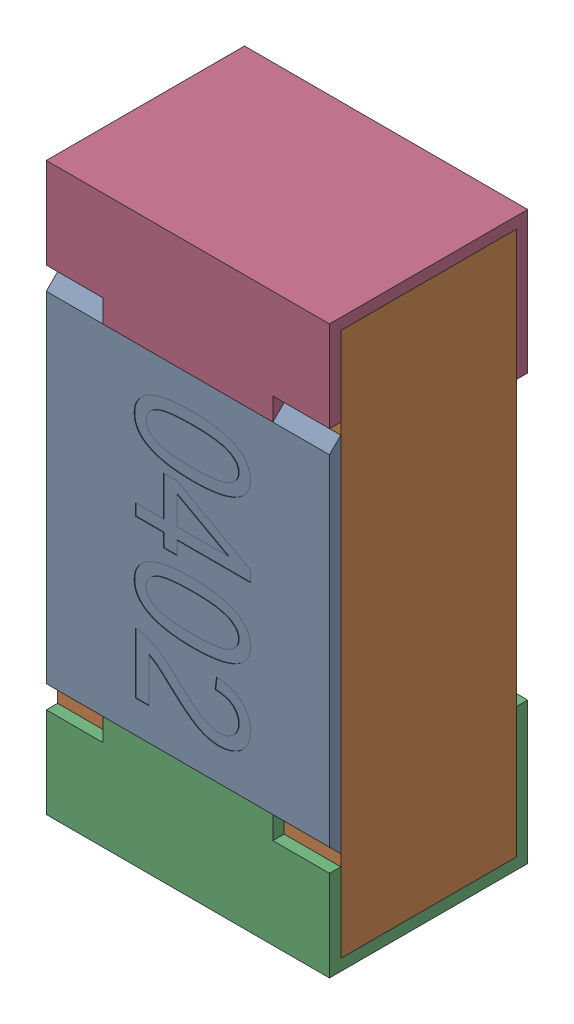
SolidWorks assembly R36, configuration Standard. Lengths in mm.
Overall size (0.5 1 0.35).
5 component instances, 4 part files, 0 mates.
Components (placement in the parent):
- R36-subassembly-1-1: R36-subassembly-1 [Standard] at (15.9 6.7999 0) x (0 -1 0) z (0 0 1) size (1 0.5 0.35)
  - User Library-R_0402-1: User Library-R_0402 [Standard] at origin size (0.64 0.5 0.02)
  - User Library-R_0402-1-1: User Library-R_0402-1 [Standard] at origin size (0.96 0.5 0.31)
  - User Library-R_0402-2-1: User Library-R_0402-2 [Standard] at origin size (0.25 0.5 0.35)
  - User Library-R_0402-3-1: User Library-R_0402-3 [Standard] at origin size (0.25 0.5 0.35)
